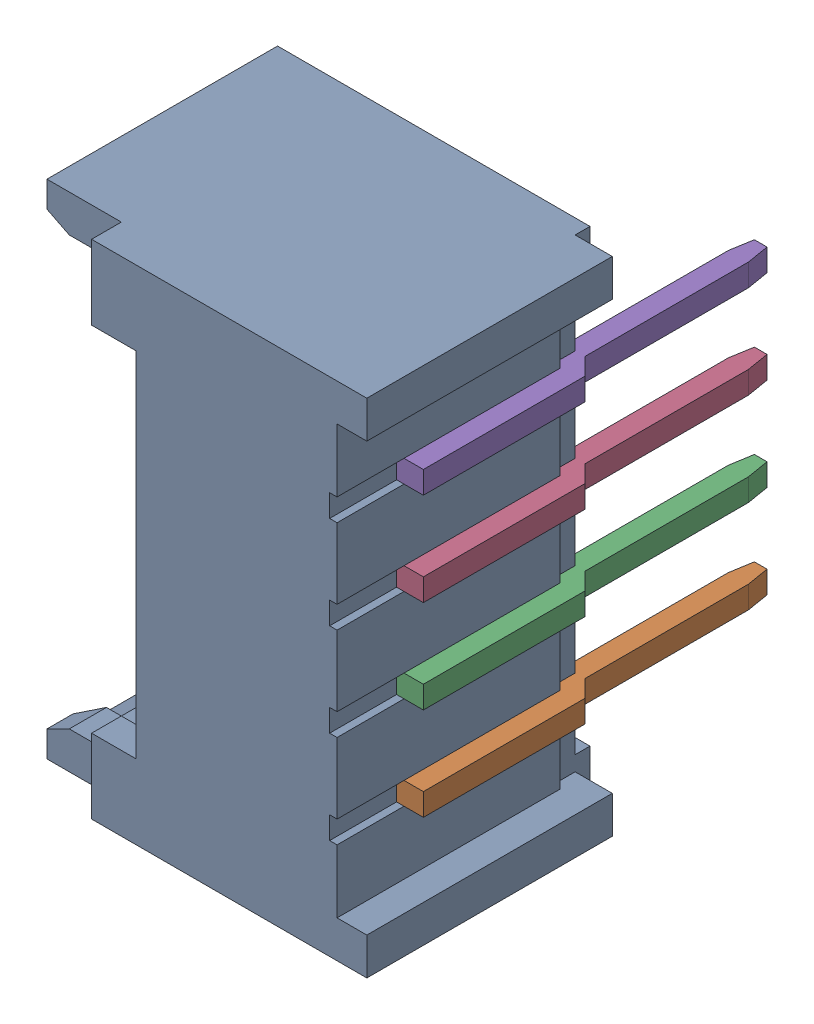
SolidWorks assembly J1_1, configuration Default. Lengths in mm.
Overall size (4.7 6.75 5.8).
6 component instances, 2 part files, 0 mates.
Components (placement in the parent):
- 653004117322-1: 653004117322 [Default] at (-1.4261 23.7749 1.8) x (0 1 0) z (-1 0 0) size (6.75 5.8 4.7)
  - 653004117322-1: 653004117322 [Default] at origin size (6.75 3.5 4.7)
  - 6530xx117322_PIN-1: 6530xx117322_PIN [Default] at (-1.875 0.375 -1.96) size (0.3 4.9 4)
  - 6530xx117322_PIN-2: 6530xx117322_PIN [Default] at (-0.625 0.375 -1.96) size (0.3 4.9 4)
  - 6530xx117322_PIN-3: 6530xx117322_PIN [Default] at (0.625 0.375 -1.96) size (0.3 4.9 4)
  - 6530xx117322_PIN-4: 6530xx117322_PIN [Default] at (1.875 0.375 -1.96) size (0.3 4.9 4)
